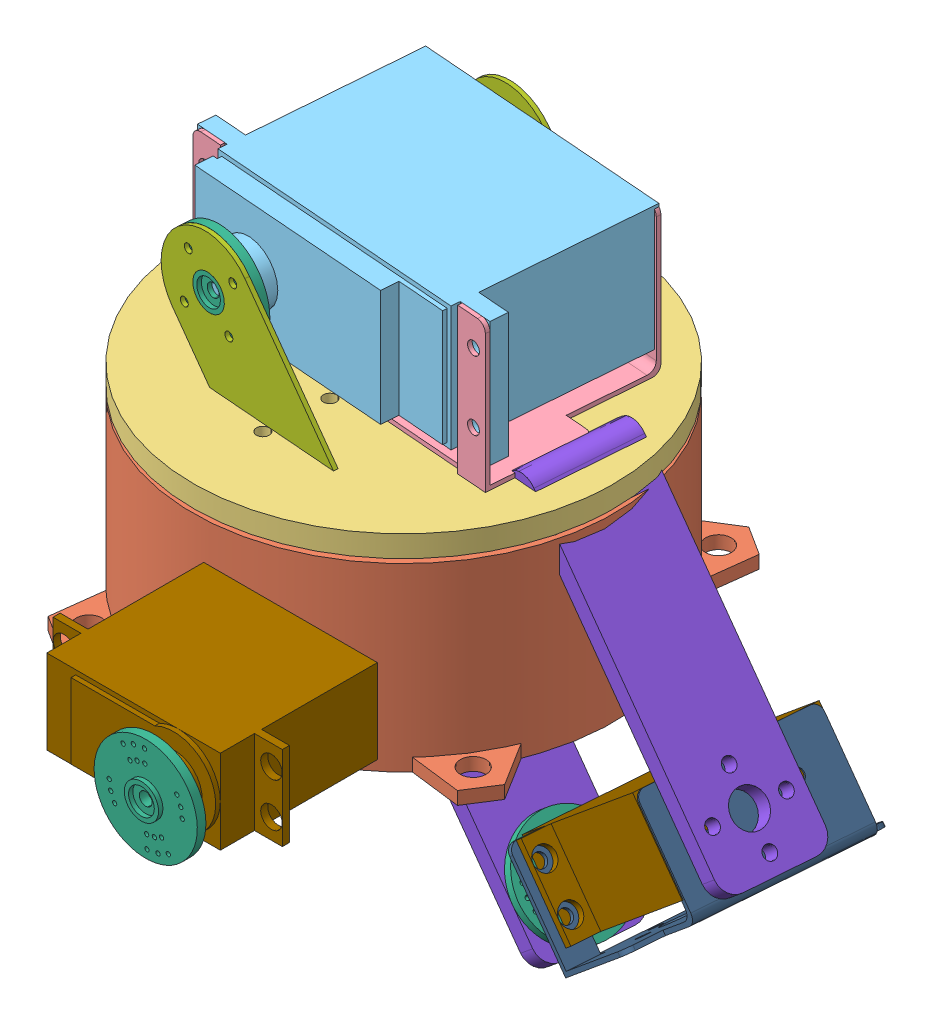
SolidWorks assembly Assem4, configuration Default. Lengths in mm.
Overall size (172.49 134 209.76).
16 component instances, 10 part files, 4 mates.
Components (placement in the parent):
- base fix 4 3-1: base fix 4 3 [Default] at (81.0127 -29.1533 87.2911) size (172.49 134 162.97) (flexible)
  - hs-422_sws-1: hs-422_sws [Default] at (6.6782 32.5822 43.0057) size (19.81 42.14 58.23)
  - base arm-1: base arm [Default] at (19.6982 18.9554 48.4147) x (0.538087 0 -0.842889) z (0.842889 0 0.538087) size (118.01 42 118.01)
  - arm base up-1: arm base up [Default] at (43.1548 54.8067 55.3554) x (0.997 0 0.077396) z (0 1 0) size (98 98 12)
  - hs 755 bracket-1: hs 755 bracket [Default] at (50.4383 89.2206 95.2511) x (-0.077396 0 0.997) z (-0.997 0 -0.077396) size (44 34 74)
  - hitec hs 755-1: hitec hs 755 [Default] at (8.8354 123.9367 22.6009) x (0 1 0) z (-0.077396 0 0.997) size (29 74 56.99)
  - servo bracket general-1: servo bracket general [Default] at (-45.5986 92.6807 76.5398) x (-0.929939 0.360557 -0.07219) z (0.077396 0 -0.997) size (24 24 6)
  - u braket joint 1-2-1: u braket joint 1-2 [Default] at (36.6166 56.6585 37.4924) x (0.077396 0 -0.997) z (-0.763747 -0.642788 -0.059288) size (66 59 24)
  - arm junc 2-1: arm junc 2 [Default] at (50.397 6.8515 63.5161) x (-0.763747 -0.642788 -0.059288) z (0.077396 0 -0.997) size (64 79 24)
- Assem3-1: Assem3 [Default] at (199.8697 -44.7296 101.6283) x (-0.077396 0 0.997) z (-0.763747 -0.642788 -0.059288) size (57 25.97 45.78) (flexible)
  - hitec hs 645-1: hitec hs 645 [Default] at (85.2365 45.0903 10.6518) size (53.34 19.56 42.35)
  - servo bracket general-1: servo bracket general [Default] at (89.022 35.0569 55.0063) x (1 0.000271 0) z (0 0 -1) size (24 24 6)
  - bracket general hs 645-1: bracket general hs 645 [Default] at (60.1619 26.0272 56.9198) x (0 0 1) z (-1 0 0) size (34 24 57)
- servo hitec 645 disk horn fix-2: servo hitec 645 disk horn fix [Default] at (135.0219 13.4929 202.5536) size (53.34 29.89 45.35) (flexible)
  - hitec hs 645-1: hitec hs 645 [Default] at (72.7388 39.6342 20.9535) size (53.34 19.56 42.35)
  - servo bracket general-1: servo bracket general [Default] at (13.3637 70.2207 65.308) x (-0.287572 0.957759 0) z (0 0 -1) size (24 24 6)
Mates (geometry in assembly coordinates):
- Coincident3: coincident anti-aligned: plane of base fix 4 3-1/arm junc 2-1 through (117.9523 -35.1912 125.6904) normal (0.763747 0.642788 0.059288); plane of Assem3-1/servo bracket general-1 through (134.1589 -55.6738 138.9846) normal (-0.763747 -0.642788 -0.059288)
- Concentric7: concentric anti-aligned: cylinder of base fix 4 3-1/arm junc 2-1 through (134.1589 -55.6738 138.9846) axis (-0.763747 -0.642788 -0.059288) radius 4; cylinder of Assem3-1/servo bracket general-1 through (133.3952 -56.3166 138.9253) axis (0.763747 0.642788 0.059288) radius 4
- Lock7: lock: unknown of ?; unknown of ?
- LimitAngle3: limit planar angle = 0 rad aligned: plane of Assem3-1/hitec hs 645-1 through (140.3045 -36.7839 149.0153) normal (-0.077396 0 0.997); plane of base fix 4 3-1/arm junc 2-1 through (131.4097 -22.3019 150.8073) normal (-0.077396 0 0.997)
